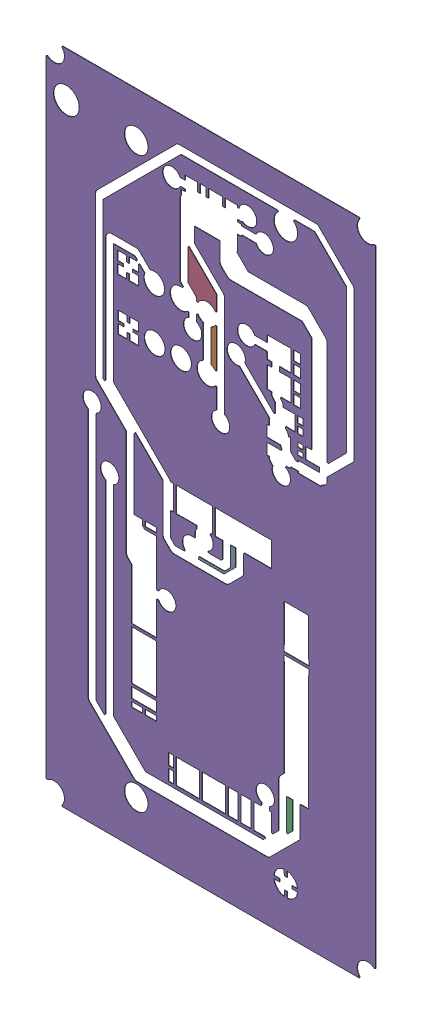
SolidWorks assembly Polygon  (GND_L01_P000) on Top Layer, configuration Predeterminado. Lengths in mm.
Overall size (31.76 63.51 0.04).
10 component instances, 5 part files, 0 mates.
Components (placement in the parent):
- Polygon Region (0 hole(s)) Top Layer-1: Polygon Region (0 hole(s)) Top Layer [Predeterminado] at (-68.317 -44.187 -0.0457) size (3.6 2.72 0.04)
  - Polygon Region (0 hole(s)) Top Layer-Part-1-1: Polygon Region (0 hole(s)) Top Layer-Part-1 [Predeterminado] at origin size (3.6 2.72 0.04)
- Polygon Region (0 hole(s)) Top Layer-1-1: Polygon Region (0 hole(s)) Top Layer-1 [Predeterminado] at (-68.317 -44.187 -0.0457) size (0.54 3.78 0.04)
  - Polygon Region (0 hole(s)) Top Layer-Part-1-1-1: Polygon Region (0 hole(s)) Top Layer-Part-1-1 [Predeterminado] at origin size (0.54 3.78 0.04)
- Polygon Region (0 hole(s)) Top Layer-2-1: Polygon Region (0 hole(s)) Top Layer-2 [Predeterminado] at (-68.317 -44.187 -0.0457) size (0.56 3.06 0.04)
  - Polygon Region (0 hole(s)) Top Layer-Part-1-2-1: Polygon Region (0 hole(s)) Top Layer-Part-1-2 [Predeterminado] at origin size (0.56 3.06 0.04)
- Polygon Region (0 hole(s)) Top Layer-3-1: Polygon Region (0 hole(s)) Top Layer-3 [Predeterminado] at (-68.317 -44.187 -0.0457) size (2.79 4.24 0.04)
  - Polygon Region (0 hole(s)) Top Layer-Part-1-3-1: Polygon Region (0 hole(s)) Top Layer-Part-1-3 [Predeterminado] at origin size (2.79 4.24 0.04)
- Polygon Region (38 hole(s)) Top Layer-1: Polygon Region (38 hole(s)) Top Layer [Predeterminado] at (-68.317 -44.187 -0.0457) size (31.76 63.51 0.04)
  - Polygon Region (38 hole(s)) Top Layer-Part-1-1: Polygon Region (38 hole(s)) Top Layer-Part-1 [Predeterminado] at origin size (31.76 63.51 0.04)
